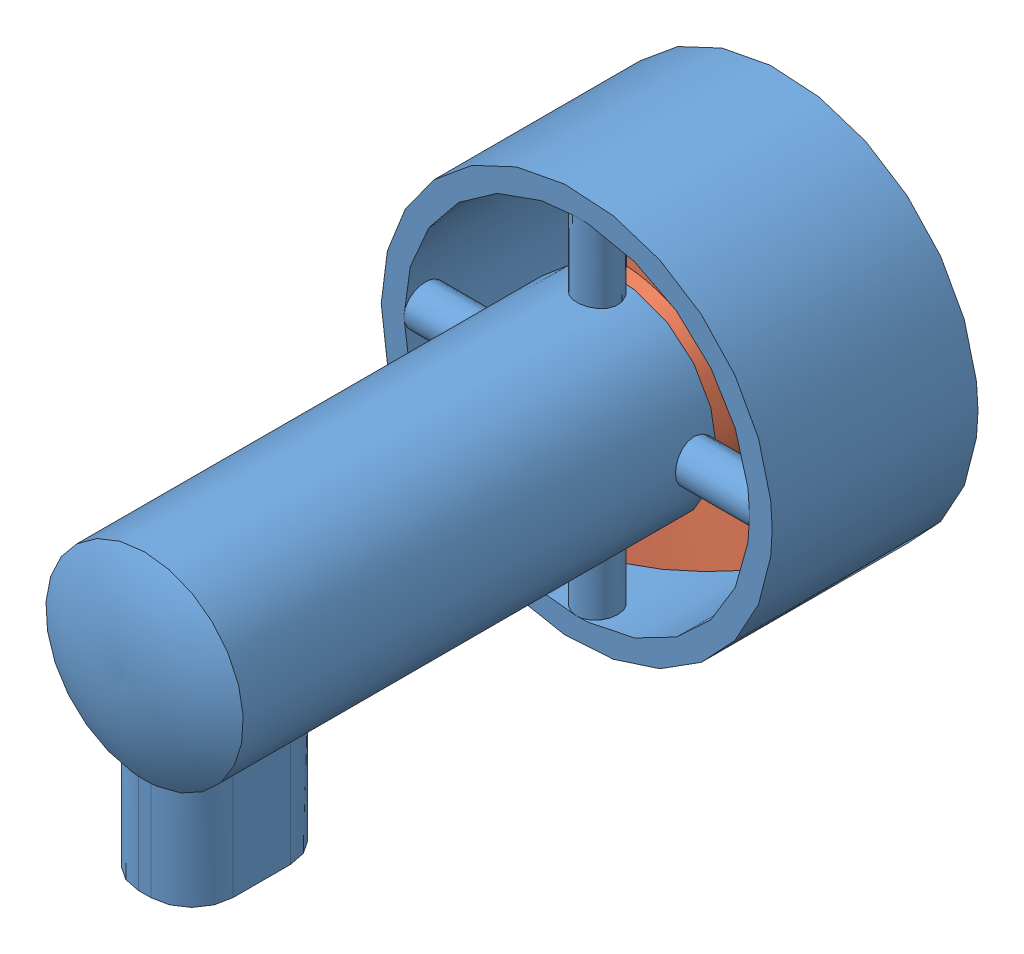
SolidWorks assembly propeller, configuration Default. Lengths in mm.
Overall size (95 95.5 160.94).
2 component instances, 2 part files, 2 mates.
Components (placement in the parent):
- thruster-1: thruster [Default] at (-44.1774 17.2499 -68.7069) size (95 95.5 160.94)
- propeller-1: propeller [Default] at (-44.1774 17.2499 -28.7069) x (0.293244 -0.956038 0) z (0 0 -1) size (76 40 35.82)
Mates (geometry in assembly coordinates):
- Concentric2: concentric anti-aligned: circle of thruster-1; circle of propeller-1
- Coincident1: coincident anti-aligned: plane of thruster-1 through (-44.1774 17.2499 -28.7069) normal (0 0 -1); plane of propeller-1 through (-44.1774 17.2499 -28.7069) normal (0 0 1)
